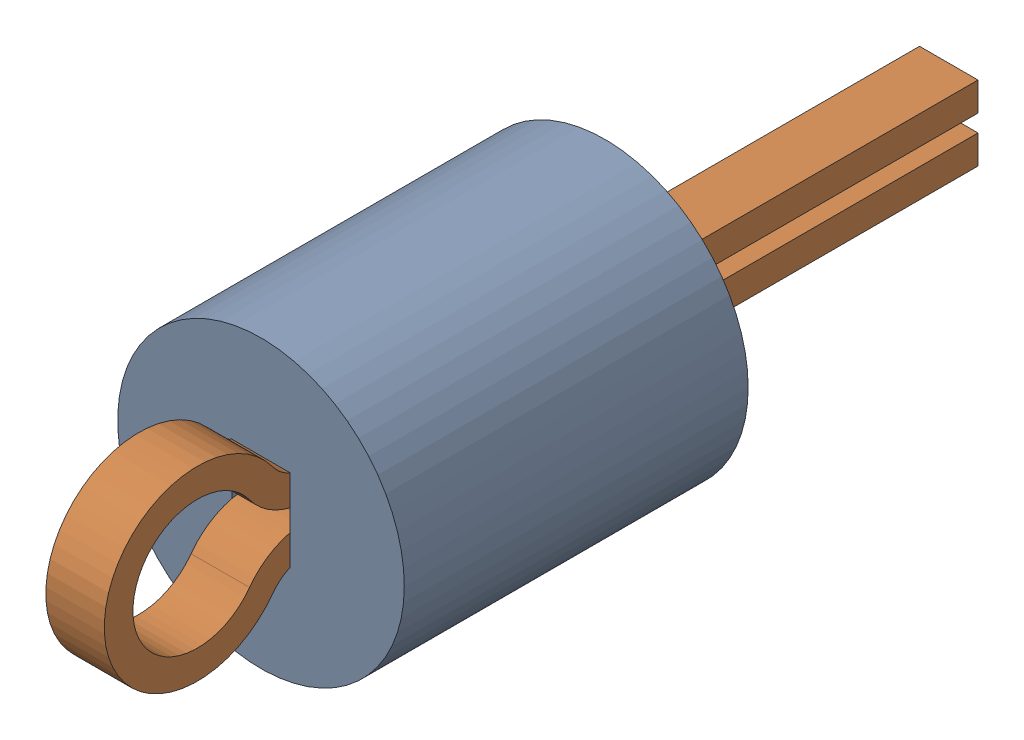
SolidWorks assembly TP9, configuration Default. Lengths in mm.
Overall size (2.5 2.5 7.62).
3 component instances, 2 part files, 0 mates.
Components (placement in the parent):
- Keystone_5002-1: Keystone_5002 [Default] at (18.7915 31.7529 0) size (2.5 2.5 7.62)
  - Keystone5002_white-1: Keystone5002_white [Default] at origin size (2.5 2.5 3)
  - Keystone500x_wire-1: Keystone500x_wire [Default] at origin size (0.51 1.62 7.62)
